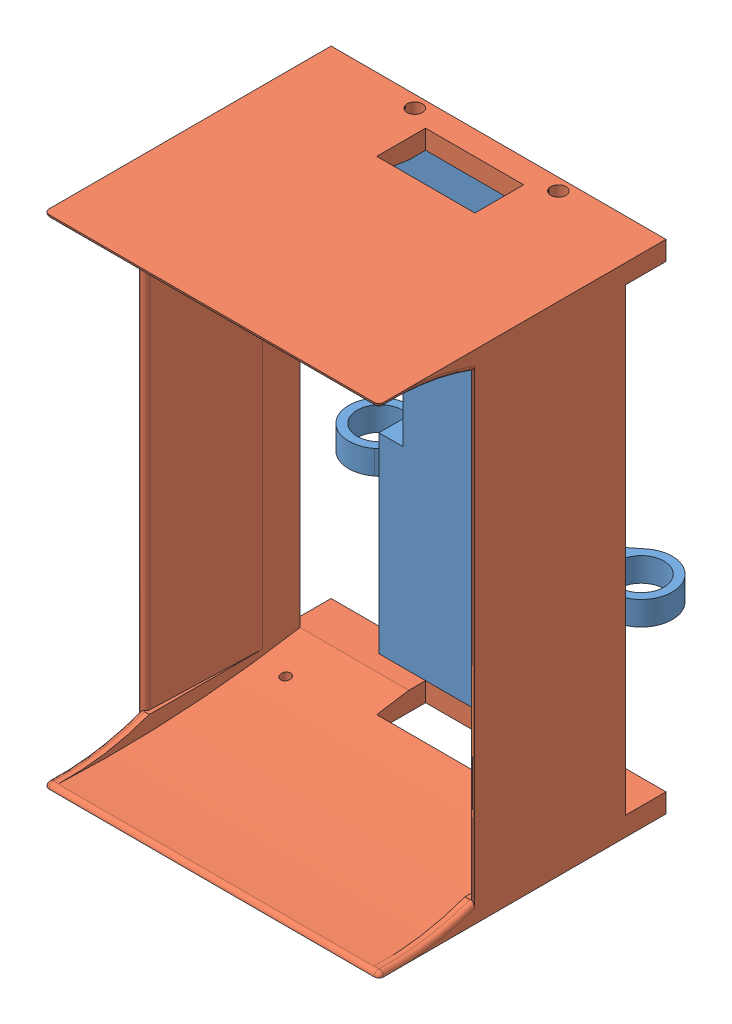
SolidWorks assembly poker case assembly, configuration Default. Lengths in mm.
Overall size (70.13 104 69).
2 component instances, 2 part files, 2 mates.
Components (placement in the parent):
- poker case base 1-1: poker case base 1 [Default] at (18.8791 38.3921 21.7185) size (67.62 96 14)
- poker case base 2-1: poker case base 2 [Default] at (20.3667 50.8549 21.7185) size (70.13 104 60)
Mates (geometry in assembly coordinates):
- Coincident1: coincident anti-aligned: plane of poker case base 1-1 through (40.3667 2.8549 26.7185) normal (0 -1 0); plane of poker case base 2-1 through (53.3667 2.8549 21.7185) normal (0 1 0)
- Concentric1: concentric aligned: cylinder of poker case base 1-1 through (5.3667 9.8549 24.2185) axis (0 -1 0) radius 1.6; cylinder of poker case base 2-1 through (5.3667 102.8549 24.2185) axis (0 -1 0) radius 1.6
